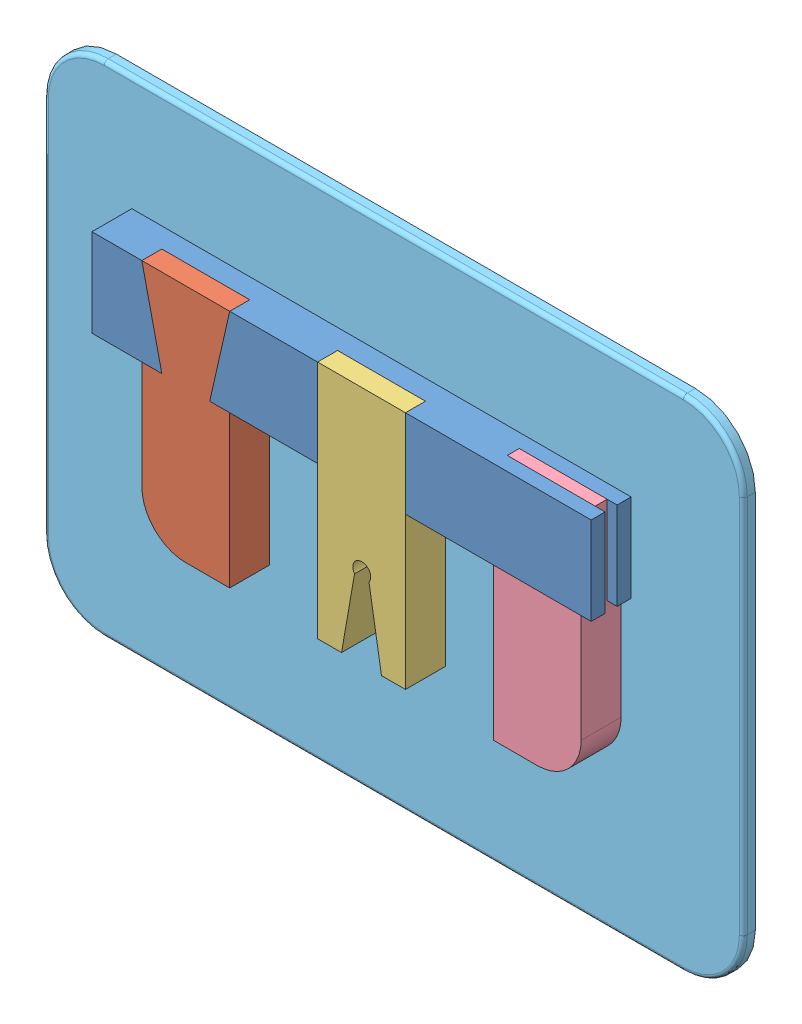
SolidWorks assembly KEYRING HOLDER, configuration Default. Lengths in mm.
Overall size (350 250 26).
5 component instances, 5 part files, 10 mates.
Components (placement in the parent):
- Long Piece-1: Long Piece [Default] at (-104.9092 19.7686 41.9286) size (250 44 20)
- Dovetial-1: Dovetial [Default] at (-79.9092 -56.2314 41.9286) size (44 120 20)
- TEE HALVING-1: TEE HALVING [Default] at (8.0908 -56.2314 41.9286) size (44 120 20)
- BRIDLE-1: BRIDLE [Default] at (96.0908 -56.2314 41.9286) size (44 120 20)
- Back Board-1: Back Board [Default] at (26.2695 -4.0854 25.9286) size (350 250 6)
Mates (geometry in assembly coordinates):
- Coincident1: coincident anti-aligned: plane of Long Piece-1 through (-79.9092 63.7686 41.9286) normal (0 0 1); plane of Dovetial-1 through (-35.9092 19.7686 41.9286) normal (0 0 -1)
- Coincident3: coincident anti-aligned: line of Long Piece-1 through (-35.9092 63.7686 41.9286) axis (-1 0 0); line of Dovetial-1 through (-79.9092 63.7686 41.9286) axis (1 0 0)
- Coincident4: coincident anti-aligned: line of Long Piece-1 through (-45.9092 19.7686 51.9286) axis (0.221621 0.975133 0); line of Dovetial-1 through (-35.9092 63.7686 51.9286) axis (-0.221621 -0.975133 0)
- Coincident5: coincident anti-aligned: plane of Long Piece-1 through (52.0908 63.7686 41.9286) normal (0 0 1); plane of TEE HALVING-1 through (52.0908 19.7686 41.9286) normal (0 0 -1)
- Coincident6: coincident anti-aligned: line of Long Piece-1 through (52.0908 63.7686 41.9286) axis (-1 0 0); line of TEE HALVING-1 through (8.0908 63.7686 41.9286) axis (1 0 0)
- Coincident7: coincident aligned: line of Long Piece-1 through (8.0908 63.7686 51.9286) axis (0 -1 0); line of TEE HALVING-1 through (8.0908 63.7686 51.9286) axis (0 -1 0)
- Coincident8: coincident anti-aligned: plane of Long Piece-1 through (96.0908 19.7686 38.9286) normal (1 0 0); plane of BRIDLE-1 through (96.0908 -56.2314 51.9286) normal (-1 0 0)
- Coincident10: coincident anti-aligned: line of Long Piece-1 through (96.0908 63.7686 38.9286) axis (0 0 1); line of BRIDLE-1 through (96.0908 63.7686 44.9286) axis (0 0 -1)
- Coincident11: coincident anti-aligned: line of Long Piece-1 through (145.0908 63.7686 38.9286) axis (-1 0 0); line of BRIDLE-1 through (96.0908 63.7686 38.9286) axis (1 0 0)
- Coincident12: coincident anti-aligned: plane of Long Piece-1 through (-104.9092 63.7686 31.9286) normal (0 0 -1); plane of Back Board-1 through (-118.7305 90.9146 31.9286) normal (0 0 1)
